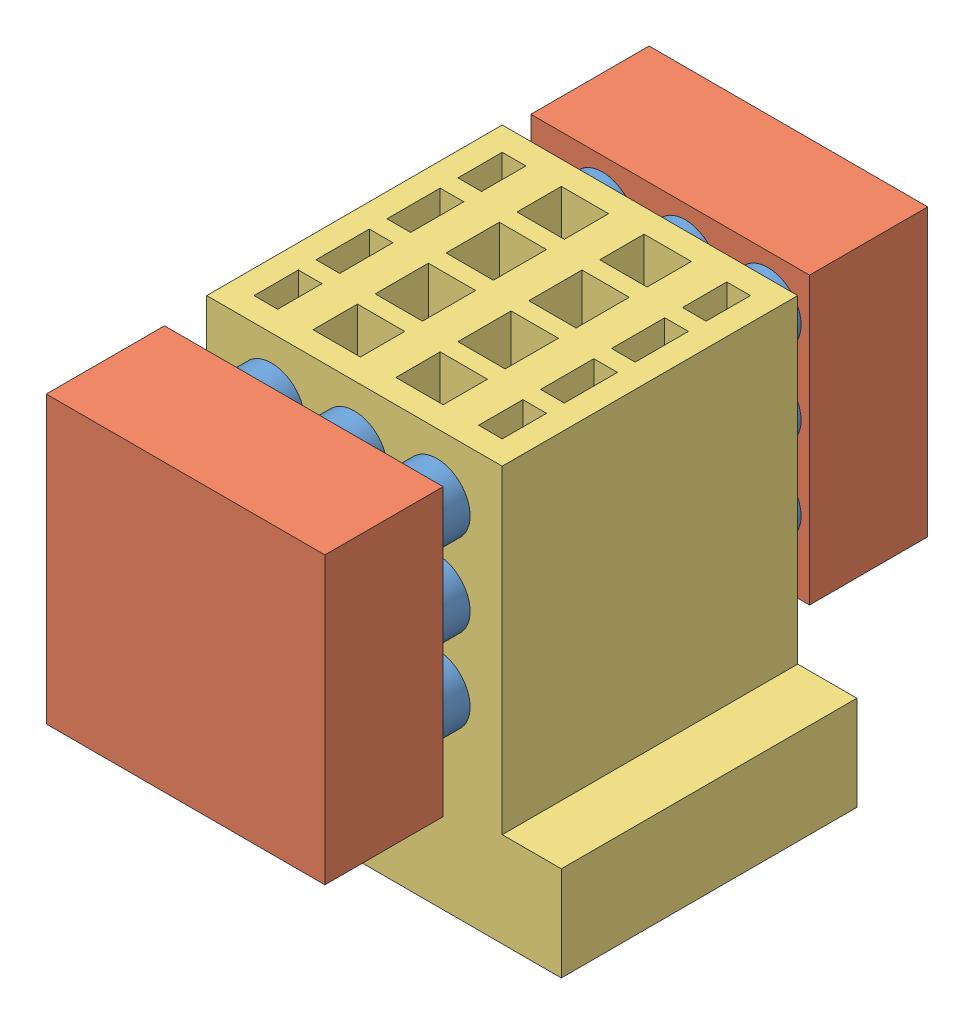
SolidWorks assembly 1.224, configuration Default. Lengths in mm.
Overall size (54.43 35 51).
5 component instances, 3 part files, 9 mates.
Components (placement in the parent):
- sensor cyli bump-1: sensor cyli bump [Default] at (-61.1671 3.1775 4.2757) size (50 30 3)
- sensorbase-1: sensorbase [Default] at (-61.1754 2.3323 17.2757) size (23.58 24.17 10)
- sensor cyli bump-2: sensor cyli bump [Default] at (-61.1671 3.1775 -23.7243) size (50 30 3)
- sensorbase-2: sensorbase [Default] at (-61.1754 2.3323 -23.7243) size (23.58 24.17 10)
- 4-长方形（泛化）-1: 4-长方形（泛化） [默认] at (-72.6123 -9.5375 1.7757) x (1 0 0) z (0 1 0) size (35 25 35)
Mates (geometry in assembly coordinates):
- 重合5: coincident anti-aligned: plane of sensor cyli bump-1 through (-79.6308 -3.5375 17.2757) normal (0 0 1); plane of sensorbase-1 through (-61.1754 2.3323 17.2757) normal (0 0 -1)
- 同心1: concentric aligned: cylinder of sensor cyli bump-1 through (-79.6308 10.4625 17.2757) axis (0 0 -1) radius 2.8; cylinder of sensor cyli bump-2 through (-79.6308 10.4625 -10.7243) axis (0 0 -1) radius 2.8
- 同心2: concentric aligned: cylinder of sensor cyli bump-1 through (-79.6308 -3.5375 17.2757) axis (0 0 -1) radius 2.8; cylinder of sensor cyli bump-2 through (-79.6308 -3.5375 -10.7243) axis (0 0 -1) radius 2.8
- 重合8: coincident anti-aligned: plane of sensor cyli bump-2 through (-85.6797 -14.6932 -13.7243) normal (0 0 -1); plane of sensorbase-2 through (-61.1754 2.3323 -13.7243) normal (0 0 1)
- 重合11: coincident aligned: plane of sensorbase-1 through (-85.6879 14.4617 27.2757) normal (-1 0 0); plane of sensorbase-2 through (-85.6879 14.4617 -13.7243) normal (-1 0 0)
- 重合12: coincident aligned: plane of sensorbase-1 through (-85.6879 14.4617 27.2757) normal (0 1 0); plane of sensorbase-2 through (-85.6879 14.4617 -13.7243) normal (0 1 0)
- 重合13: coincident: plane of sensor cyli bump-1 through (-85.6797 -14.6932 14.2757) normal (0 0 -1); plane of 4-长方形（泛化）-1 through (-85.82 15.4625 14.2757) normal (0 0 1)
- 重合16: coincident: line of sensor cyli bump-1 through (-85.6797 10.4625 14.2757) axis (1 0 0); line of 4-长方形（泛化）-1 through (-85.1123 10.4625 14.2757) axis (1 0 0)
- 重合17: coincident anti-aligned: line of sensor cyli bump-1 through (-79.6308 7.6625 14.2757) axis (0 1 0); line of 4-长方形（泛化）-1 through (-79.6308 15.4625 14.2757) axis (0 -1 0)
